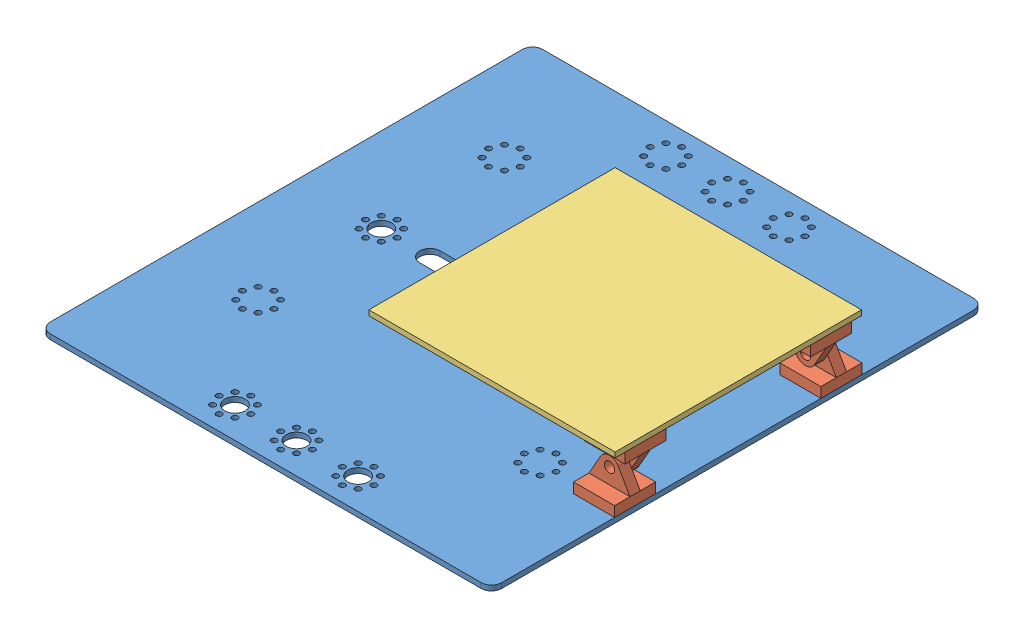
SolidWorks assembly FullDumpingMechanism, configuration Default. Lengths in mm.
Overall size (279.4 38.1 304.8).
8 component instances, 4 part files, 12 mates.
Components (placement in the parent):
- Top plate 2-2: Top plate 2 [Default] at (140.0603 3.175 152.73) x (1 0 0) z (0 -1 0) size (279.4 304.8 3.17)
- DumpingBracket-1: DumpingBracket [Default] at (127.3603 6.35 63.83) size (25.4 22.2 25.4)
- DumpingBracket-3: DumpingBracket [Default] at (127.3603 31.75 57.48) x (-1 0 0) z (0 0 1) size (25.4 22.2 25.4)
- DumpingBracket-4: DumpingBracket [Default] at (127.3603 6.35 -63.83) size (25.4 22.2 25.4)
- DumpingBracket-5: DumpingBracket [Default] at (127.3603 31.75 -57.48) x (-1 0 0) z (0 0 1) size (25.4 22.2 25.4)
- DumpingPlate-1: DumpingPlate [Default] at (63.8603 36.5125 0) size (152.4 3.17 152.4)
- DumpingSupport-1: DumpingSupport [Default] at (10.3451 3.175 36.4861) size (6.35 31.75 6.35)
- DumpingSupport-2: DumpingSupport [Default] at (10.3451 3.175 -36.4861) size (6.35 31.75 6.35)
Mates (geometry in assembly coordinates):
- Coincident2: coincident anti-aligned: plane of Top plate 2-2 through (140.0603 0 152.73) normal (0 -1 0)
- Coincident5: coincident anti-aligned: plane of Top plate 2-2 through (140.0603 3.175 152.73) normal (0 1 0); plane of DumpingBracket-1 through (114.6603 3.175 76.53) normal (0 -1 0)
- Coincident6: coincident aligned: plane of Top plate 2-2 through (140.0603 0 152.73) normal (1 0 0); plane of DumpingBracket-1 through (140.0603 3.175 76.53) normal (1 0 0)
- Distance1: distance = 76.2 mm aligned: plane of Top plate 2-2 through (140.0603 0 152.73) normal (0 0 1); plane of DumpingBracket-1 through (127.3603 6.35 76.53) normal (0 0 1)
- Coincident8: coincident anti-aligned: plane of DumpingBracket-1 through (127.3603 19.05 60.655) normal (0 0 -1); plane of DumpingBracket-3 through (127.3603 19.05 60.655) normal (0 0 1)
- Concentric1: concentric aligned: circle of DumpingBracket-1; circle of DumpingBracket-3
- Coincident10: coincident anti-aligned: plane of DumpingBracket-3 through (140.0603 34.925 70.18) normal (0 1 0); plane of DumpingPlate-1 through (140.0603 34.925 76.2) normal (0 -1 0)
- Coincident11: coincident aligned: plane of DumpingBracket-3 through (140.0603 34.925 70.18) normal (1 0 0); plane of DumpingPlate-1 through (140.0603 38.1 76.2) normal (1 0 0)
- Coincident12: coincident aligned: plane of DumpingPlate-1 through (63.8603 36.5125 0) normal (0 0 1)
- Parallel3: parallel anti-aligned: plane of Top plate 2-2 through (140.0603 3.175 152.73) normal (0 1 0); plane of DumpingPlate-1
- Coincident14: coincident anti-aligned: plane of Top plate 2-2 through (140.0603 3.175 152.73) normal (0 1 0); plane of DumpingSupport-1 through (10.3451 3.175 36.4861) normal (0 -1 0)
- LimitAngle1: limit planar angle = 0 rad anti-aligned: plane of DumpingSupport-2 through (10.3451 34.925 -36.4861) normal (0 1 0); plane of DumpingPlate-1 through (140.0603 34.925 76.2) normal (0 -1 0)
